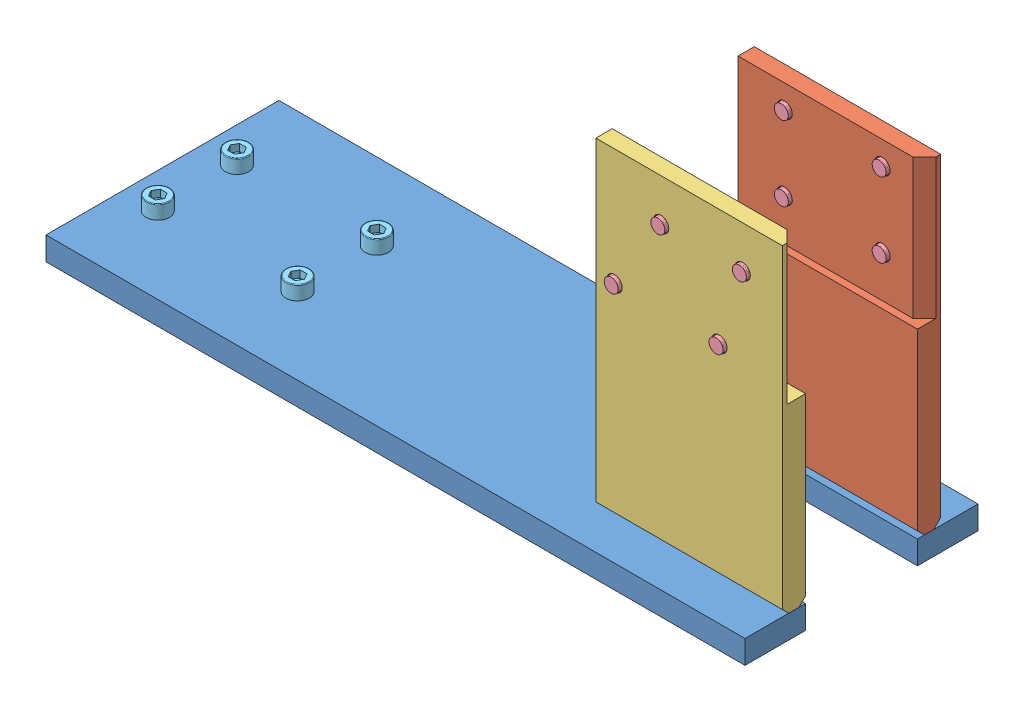
SolidWorks assembly Montagem1, configuration Valor predeterminado. Lengths in mm.
Overall size (300 150 100).
15 component instances, 5 part files, 22 mates.
Components (placement in the parent):
- peça 1-1: peça 1 [Valor predeterminado] at (-11.348 -23.9119 300) size (300 10 100)
- Peça4-1: Peça4 [Valor predeterminado] at (138.652 119.0881 266) x (0 1 0) z (0 0 1) size (138 80 10)
- Peça5-1: Peça5 [Valor predeterminado] at (58.652 119.0881 327) x (0 1 0) z (0 0 -1) size (138 80 10)
- countersunk flat head cross recess screw_iso-4: countersunk flat head cross recess screw_iso [ISO 7046-1 - M6 x 8 - Z - 8C] at (121.652 101.0881 327.42) x (0 0 1) z (-0.999617 -0.027688 0) size (8 11.3 11.3)
- countersunk flat head cross recess screw_iso-5: countersunk flat head cross recess screw_iso [ISO 7046-1 - M6 x 8 - Z - 8C] at (86.652 101.0881 327.42) x (0 0 1) z (-0.977104 0.212764 0) size (8 11.3 11.3)
- countersunk flat head cross recess screw_iso-6: countersunk flat head cross recess screw_iso [ISO 7046-1 - M6 x 8 - Z - 8C] at (111.652 69.0881 327.42) x (0 0 1) z (-0.991454 0.130453 0) size (8 11.3 11.3)
- countersunk flat head cross recess screw_iso-7: countersunk flat head cross recess screw_iso [ISO 7046-1 - M6 x 8 - Z - 8C] at (66.652 69.0881 327.42) x (0 0 1) z (-0.988877 0.148735 0) size (8 11.3 11.3)
- countersunk flat head cross recess screw_iso-8: countersunk flat head cross recess screw_iso [ISO 7046-1 - M6 x 8 - Z - 8C] at (78.652 109.0881 266.42) x (0 0 1) z (-0.978307 0.207161 0) size (8 11.3 11.3)
- countersunk flat head cross recess screw_iso-9: countersunk flat head cross recess screw_iso [ISO 7046-1 - M6 x 8 - Z - 8C] at (120.652 109.0881 266.42) x (0 0 1) z (-0.999445 -0.033321 0) size (8 11.3 11.3)
- countersunk flat head cross recess screw_iso-10: countersunk flat head cross recess screw_iso [ISO 7046-1 - M6 x 8 - Z - 8C] at (78.652 77.0881 266.42) x (0 0 1) z (-0.982055 0.188596 0) size (8 11.3 11.3)
- countersunk flat head cross recess screw_iso-11: countersunk flat head cross recess screw_iso [ISO 7046-1 - M6 x 8 - Z - 8C] at (120.652 77.0881 266.42) x (0 0 1) z (-0.988719 0.14978 0) size (8 11.3 11.3)
- socket head cap screw_iso-2: socket head cap screw_iso [ISO 4762 M6 x 12 - 12N] at (-146.348 -12.9119 317) x (0 -1 0) z (0 0 1) size (18 10 10)
- socket head cap screw_iso-3: socket head cap screw_iso [ISO 4762 M6 x 12 - 12N] at (-146.348 -12.9119 283) x (0 -1 0) z (0 0 1) size (18 10 10)
- socket head cap screw_iso-4: socket head cap screw_iso [ISO 4762 M6 x 12 - 12N] at (-86.348 -12.9119 283) x (0 -1 0) z (0 0 1) size (18 10 10)
- socket head cap screw_iso-5: socket head cap screw_iso [ISO 4762 M6 x 12 - 12N] at (-86.348 -12.9119 317) x (0 -1 0) z (0 0 1) size (18 10 10)
Mates (geometry in assembly coordinates):
- Coincidente1: coincident anti-aligned: plane of peça 1-1 through (-11.348 -18.9119 300) normal (0 1 0); plane of Peça4-1 through (138.652 -18.9119 276) normal (0 -1 0)
- Coincidente2: coincident aligned: plane of peça 1-1 through (138.652 -18.9119 276) normal (1 0 0); plane of Peça4-1 through (138.652 119.0881 276) normal (1 0 0)
- Coincidente3: coincident aligned: plane of peça 1-1 through (58.652 -18.9119 276) normal (0 0 1); plane of Peça4-1 through (138.652 119.0881 276) normal (0 0 1)
- Coincidente4: coincident aligned: plane of peça 1-1 through (138.652 -18.9119 350) normal (1 0 0); plane of Peça5-1 through (138.652 119.0881 327) normal (1 0 0)
- Coincidente5: coincident anti-aligned: plane of peça 1-1 through (-11.348 -18.9119 300) normal (0 1 0); plane of Peça5-1 through (138.652 -18.9119 326.8644) normal (0 -1 0)
- Coincidente6: coincident aligned: plane of peça 1-1 through (58.652 -18.9119 324) normal (0 0 -1); plane of Peça5-1 through (138.652 -16.0476 324) normal (0 0 -1)
- Coincidente7: coincident aligned: cone of Peça5-1 through (121.652 101.0881 327) axis (0 0 1); cone of countersunk flat head cross recess screw_iso-4 through (121.652 101.0881 328.07) axis (0 0 1)
- Coincidente8: coincident aligned: cone of Peça5-1 through (86.652 101.0881 327) axis (0 0 1); cone of countersunk flat head cross recess screw_iso-5 through (86.652 101.0881 328.07) axis (0 0 1)
- Coincidente9: coincident aligned: cone of Peça5-1 through (111.652 69.0881 327) axis (0 0 1); cone of countersunk flat head cross recess screw_iso-6 through (111.652 69.0881 328.07) axis (0 0 1)
- Coincidente10: coincident aligned: cone of Peça5-1 through (66.652 69.0881 327) axis (0 0 1); cone of countersunk flat head cross recess screw_iso-7 through (66.652 69.0881 328.07) axis (0 0 1)
- Coincidente11: coincident aligned: cone of Peça4-1 through (78.652 109.0881 266) axis (0 0 1); cone of countersunk flat head cross recess screw_iso-8 through (78.652 109.0881 267.07) axis (0 0 1)
- Coincidente12: coincident aligned: cone of Peça4-1 through (120.652 109.0881 266) axis (0 0 1); cone of countersunk flat head cross recess screw_iso-9 through (120.652 109.0881 267.07) axis (0 0 1)
- Coincidente13: coincident aligned: cone of Peça4-1 through (78.652 77.0881 266) axis (0 0 1); cone of countersunk flat head cross recess screw_iso-10 through (78.652 77.0881 267.07) axis (0 0 1)
- Coincidente14: coincident aligned: cone of Peça4-1 through (120.652 77.0881 266) axis (0 0 1); cone of countersunk flat head cross recess screw_iso-11 through (120.652 77.0881 267.07) axis (0 0 1)
- Concêntrico1: concentric anti-aligned: cone of peça 1-1 through (-146.348 -18.9119 317) axis (0 -1 0); cylinder of socket head cap screw_iso-2 through (-146.348 18.8381 317) axis (0 1 0) radius 5
- Coincidente15: coincident anti-aligned: plane of peça 1-1 through (-11.348 -18.9119 300) normal (0 1 0); plane of socket head cap screw_iso-2 through (-141.348 -18.9119 317) normal (0 -1 0)
- Concêntrico2: concentric anti-aligned: cone of peça 1-1 through (-146.348 -18.9119 283) axis (0 -1 0); cylinder of socket head cap screw_iso-3 through (-146.348 18.8381 283) axis (0 1 0) radius 5
- Coincidente16: coincident anti-aligned: plane of peça 1-1 through (-11.348 -18.9119 300) normal (0 1 0); plane of socket head cap screw_iso-3 through (-141.348 -18.9119 283) normal (0 -1 0)
- Concêntrico3: concentric anti-aligned: cone of peça 1-1 through (-86.348 -18.9119 283) axis (0 -1 0); cylinder of socket head cap screw_iso-4 through (-86.348 18.8381 283) axis (0 1 0) radius 5
- Coincidente17: coincident anti-aligned: plane of peça 1-1 through (-11.348 -18.9119 300) normal (0 1 0); plane of socket head cap screw_iso-4 through (-81.348 -18.9119 283) normal (0 -1 0)
- Concêntrico4: concentric anti-aligned: cone of peça 1-1 through (-86.348 -18.9119 317) axis (0 -1 0); cylinder of socket head cap screw_iso-5 through (-86.348 18.8381 317) axis (0 1 0) radius 5
- Coincidente18: coincident anti-aligned: plane of peça 1-1 through (-11.348 -18.9119 300) normal (0 1 0); plane of socket head cap screw_iso-5 through (-81.348 -18.9119 317) normal (0 -1 0)
